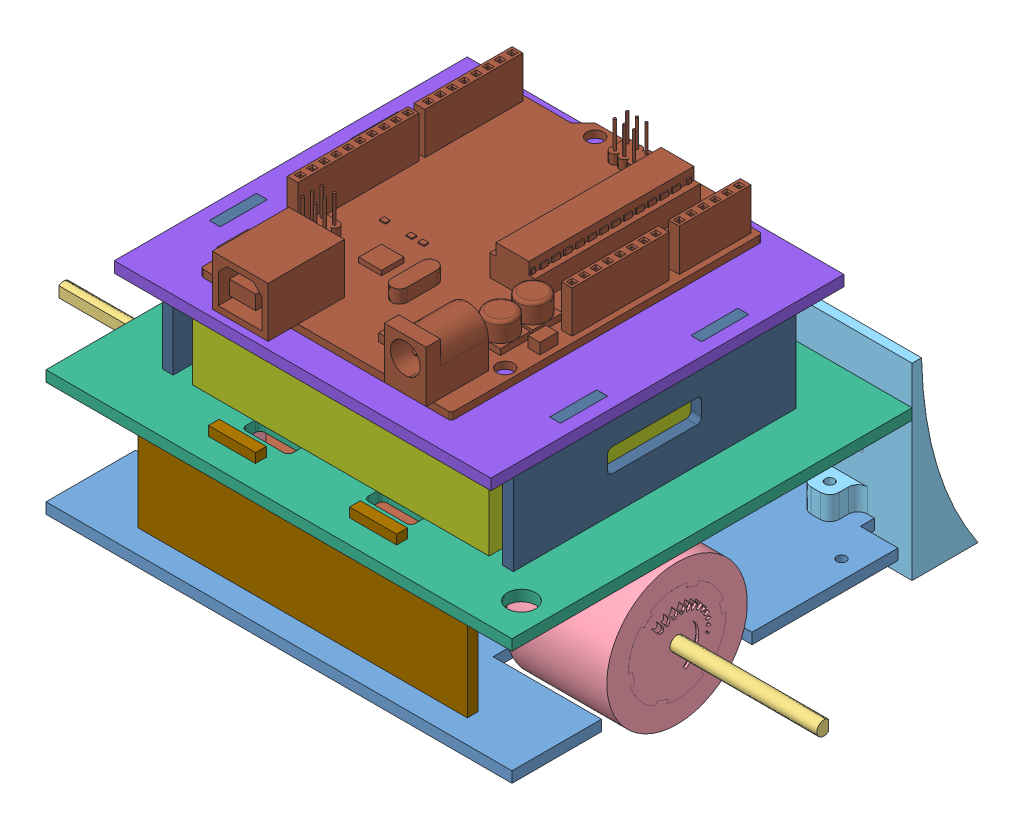
SolidWorks assembly Sumo Kit Assy V4.1, configuration Default. Lengths in mm.
Overall size (161.5 75.38 99).
14 component instances, 11 part files, 34 mates.
Components (placement in the parent):
- Bottom Plate V2.1 2.3mm-1: Bottom Plate V2.1 2.3mm [Default] at (27.6373 46.2645 76.2941) size (99 2.3 85)
- Dual Motor Mount V3-1: Dual Motor Mount V3 [Default] at (2.6373 48.5645 104.0441) size (50 16.9 25.5)
- FingerTech_Gold_Spark_16mm_motor-1: FingerTech_Gold_Spark_16mm_motor [Default] at (59.3327 54.5645 91.2941) x (-1 0 0) z (0 1 0) size (79.35 17.99 15.58)
- FingerTech_Gold_Spark_16mm_motor-2: FingerTech_Gold_Spark_16mm_motor [Default] at (-4.0581 54.5645 91.2941) x (1 0 0) z (0 1 0) size (79.35 17.99 15.58)
- MiniSumo_wheel_1125-1: MiniSumo_wheel_1125 [Default] at (-21.9327 54.5645 91.2941) x (1 0 0) z (0 0.972191 0.234191) size (21.59 29.84 29.84)
- MiniSumo_wheel_1125-2: MiniSumo_wheel_1125 [Default] at (77.2073 54.5645 91.2941) x (-1 0 0) z (0 0.653097 -0.757275) size (21.59 29.84 29.84)
- 3D Print Ramp V4.2-1: 3D Print Ramp V4.2 [Default] at (77.1373 41.0645 41.2941) x (0 0 -1) z (1 0 0) size (20 40 99)
- Mid Plate V1.2 2.3mm-1: Mid Plate V1.2 2.3mm [Default] at (27.6373 70.5645 76.2941) size (99 2.3 85)
- 4AA_Battery Holder-1: 4AA_Battery Holder [Default] at (-3.5088 72.8645 113.5113) x (1 0 0) z (0 1 0) size (63 58 16)
- Top Plate V1.1 2.3mm-1: Top Plate V1.1 2.3mm [Default] at (-12.3627 92.8645 121.2941) size (80 2.3 75)
- Back Bracket V2 2.3mm-2: Back Bracket V2 2.3mm [Default] at (-7.3627 70.5645 121.2941) x (1 0 0) z (0 1 0) size (70 2.3 28.6)
- Side Bracket V2.1 2.3mm-2: Side Bracket V2.1 2.3mm [Default] at (-9.6627 72.8645 113.7941) x (0 0 -1) z (0 -1 0) size (60 2.3 24.6)
- Side Bracket V2.1 2.3mm-3: Side Bracket V2.1 2.3mm [Default] at (62.6373 92.8645 53.7941) x (0 0 1) z (0 1 0) size (60 2.3 24.6)
- uploads-b4-22-56-eb-53-Arduino.ipt1-1: uploads-b4-22-56-eb-53-Arduino.ipt1 [Default] at (54.2771 96.4474 50.234) x (0.000785 0 -1) z (1 0 0.000785) size (74.93 14.99 53.34)
Mates (geometry in assembly coordinates):
- Coincident1: coincident anti-aligned: plane of Bottom Plate V2.1 2.3mm-1 through (27.6373 48.5645 76.2941) normal (0 1 0); plane of Dual Motor Mount V3-1 through (2.6373 48.5645 104.0441) normal (0 -1 0)
- Coincident2: coincident anti-aligned: circle of Bottom Plate V2.1 2.3mm-1; circle of Dual Motor Mount V3-1
- Coincident5: coincident anti-aligned: circle of Bottom Plate V2.1 2.3mm-1; circle of Dual Motor Mount V3-1
- Concentric1: concentric anti-aligned: circle of Dual Motor Mount V3-1; circle of FingerTech_Gold_Spark_16mm_motor-1
- Coincident7: coincident anti-aligned: plane of Dual Motor Mount V3-1 through (32.6373 48.5645 83.5441) normal (1 0 0); plane of FingerTech_Gold_Spark_16mm_motor-1 through (32.6373 50.5674 87.297) normal (-1 0 0)
- Parallel2: parallel anti-aligned: plane of Bottom Plate V2.1 2.3mm-1 through (27.6373 48.5645 76.2941) normal (0 1 0); plane of FingerTech_Gold_Spark_16mm_motor-1 through (57.454 48.4645 95.4941) normal (0 -1 0)
- Concentric2: concentric anti-aligned: circle of Dual Motor Mount V3-1; circle of FingerTech_Gold_Spark_16mm_motor-2
- Coincident9: coincident anti-aligned: plane of Dual Motor Mount V3-1 through (22.6373 48.5645 83.5441) normal (-1 0 0); plane of FingerTech_Gold_Spark_16mm_motor-2 through (22.6373 50.5674 95.2912) normal (1 0 0)
- Parallel3: parallel anti-aligned: plane of Bottom Plate V2.1 2.3mm-1 through (27.6373 48.5645 76.2941) normal (0 1 0); plane of FingerTech_Gold_Spark_16mm_motor-2 through (-2.1794 48.4645 87.0941) normal (0 -1 0)
- Concentric3: concentric anti-aligned: circle of FingerTech_Gold_Spark_16mm_motor-2; circle of MiniSumo_wheel_1125-1
- Coincident11: coincident anti-aligned: plane of FingerTech_Gold_Spark_16mm_motor-2 through (-15.5827 46.7468 99.1118) normal (-1 0 0); plane of MiniSumo_wheel_1125-1 through (-15.5827 61.0854 101.9537) normal (1 0 0)
- Concentric4: concentric anti-aligned: circle of FingerTech_Gold_Spark_16mm_motor-1; circle of MiniSumo_wheel_1125-2
- Coincident12: coincident anti-aligned: plane of FingerTech_Gold_Spark_16mm_motor-1 through (70.8573 46.7468 83.4764) normal (1 0 0); plane of MiniSumo_wheel_1125-2 through (70.8573 53.6439 78.832) normal (-1 0 0)
- Coincident13: coincident anti-aligned: plane of Bottom Plate V2.1 2.3mm-1 through (27.6373 48.5645 76.2941) normal (0 1 0); plane of 3D Print Ramp V4.2-1 through (59.6373 48.5645 47.2941) normal (0 -1 0)
- Coincident14: coincident anti-aligned: circle of Bottom Plate V2.1 2.3mm-1; circle of 3D Print Ramp V4.2-1
- Coincident15: coincident anti-aligned: circle of Bottom Plate V2.1 2.3mm-1; circle of 3D Print Ramp V4.2-1
- Coincident19: coincident anti-aligned: plane of Mid Plate V1.2 2.3mm-1 through (27.6373 72.8645 76.2941) normal (0 1 0); plane of 4AA_Battery Holder-1 through (-3.5088 72.8645 113.5113) normal (0 -1 0)
- Parallel4: parallel aligned: line of Mid Plate V1.2 2.3mm-1 through (77.1373 72.8645 41.2941) axis (-1 0 0); line of 4AA_Battery Holder-1 through (59.4912 72.8645 55.5113) axis (-1 0 0)
- Coincident24: coincident anti-aligned: plane of 3D Print Ramp V4.2-1 through (44.6373 70.5645 47.2941) normal (0 1 0); plane of Mid Plate V1.2 2.3mm-1 through (27.6373 70.5645 76.2941) normal (0 -1 0)
- Coincident25: coincident aligned: circle of 3D Print Ramp V4.2-1; circle of Mid Plate V1.2 2.3mm-1
- Coincident26: coincident anti-aligned: plane of Bottom Plate V2.1 2.3mm-1 through (27.6373 48.5645 76.2941) normal (0 1 0); plane of Back Bracket V2 2.3mm-2 through (17.6373 48.5645 118.9941) normal (0 -1 0)
- Coincident27: coincident anti-aligned: plane of Bottom Plate V2.1 2.3mm-1 through (37.6373 46.2645 121.2941) normal (1 0 0); plane of Back Bracket V2 2.3mm-2 through (37.6373 48.5645 118.9941) normal (-1 0 0)
- Coincident28: coincident anti-aligned: plane of Bottom Plate V2.1 2.3mm-1 through (37.6373 46.2645 121.2941) normal (0 0 -1); plane of Back Bracket V2 2.3mm-2 through (-7.3627 70.5645 121.2941) normal (0 0 1)
- Coincident29: coincident anti-aligned: plane of Mid Plate V1.2 2.3mm-1 through (27.6373 72.8645 76.2941) normal (0 1 0); plane of Side Bracket V2.1 2.3mm-2 through (-7.3627 72.8645 93.7941) normal (0 -1 0)
- Coincident30: coincident anti-aligned: plane of Mid Plate V1.2 2.3mm-1 through (-9.6627 70.5645 63.7941) normal (1 0 0); plane of Side Bracket V2.1 2.3mm-2 through (-9.6627 72.8645 113.7941) normal (-1 0 0)
- Coincident31: coincident aligned: circle of 3D Print Ramp V4.2-1; circle of Mid Plate V1.2 2.3mm-1
- Coincident32: coincident anti-aligned: plane of Mid Plate V1.2 2.3mm-1 through (-9.6627 70.5645 73.7941) normal (0 0 -1); plane of Side Bracket V2.1 2.3mm-2 through (-7.3627 72.8645 73.7941) normal (0 0 1)
- Coincident33: coincident anti-aligned: plane of Mid Plate V1.2 2.3mm-1 through (27.6373 72.8645 76.2941) normal (0 1 0); plane of Side Bracket V2.1 2.3mm-3 through (64.9373 72.8645 73.7941) normal (0 -1 0)
- Coincident34: coincident anti-aligned: plane of Mid Plate V1.2 2.3mm-1 through (64.9373 70.5645 63.7941) normal (-1 0 0); plane of Side Bracket V2.1 2.3mm-3 through (64.9373 92.8645 53.7941) normal (1 0 0)
- Coincident35: coincident anti-aligned: plane of Mid Plate V1.2 2.3mm-1 through (62.6373 70.5645 63.7941) normal (0 0 1); plane of Side Bracket V2.1 2.3mm-3 through (64.9373 72.8645 63.7941) normal (0 0 -1)
- Coincident36: coincident anti-aligned: plane of Top Plate V1.1 2.3mm-1 through (-12.3627 92.8645 121.2941) normal (0 -1 0); plane of Side Bracket V2.1 2.3mm-2 through (-7.3627 92.8645 93.7941) normal (0 1 0)
- Coincident37: coincident anti-aligned: plane of Top Plate V1.1 2.3mm-1 through (-7.3627 102.8645 93.7941) normal (0 0 1); plane of Side Bracket V2.1 2.3mm-2 through (-7.3627 95.1645 93.7941) normal (0 0 -1)
- Coincident38: coincident anti-aligned: plane of Top Plate V1.1 2.3mm-1 through (-9.6627 102.8645 93.7941) normal (1 0 0); plane of Side Bracket V2.1 2.3mm-2 through (-9.6627 72.8645 113.7941) normal (-1 0 0)
- Concentric6: concentric aligned: circle of Top Plate V1.1 2.3mm-1; circle of uploads-b4-22-56-eb-53-Arduino.ipt1-1
